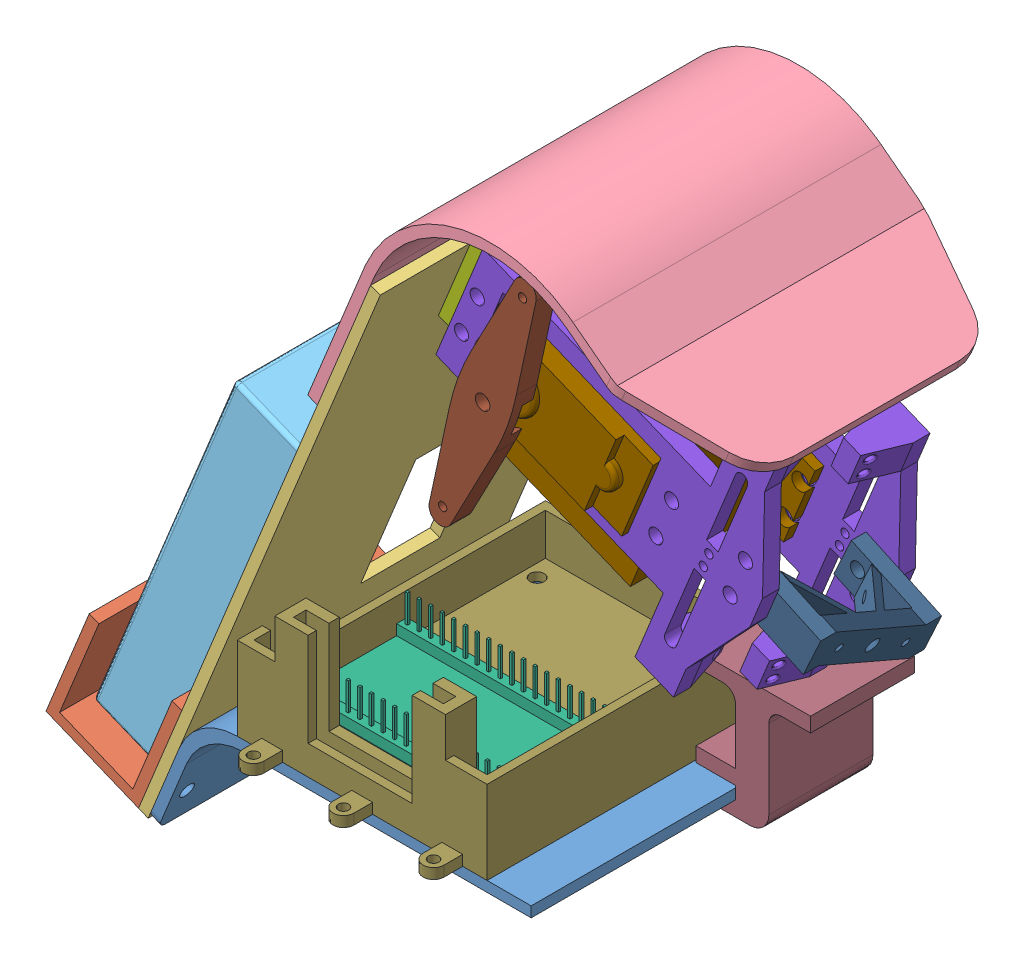
SolidWorks assembly Assieme_Completo, configuration Exploded View. Lengths in mm.
Overall size (179.46 180.65 88).
16 component instances, 13 part files, 47 mates.
Components (placement in the parent):
- Base_Shoulder Adapter-1: Base_Shoulder Adapter [Default] at (14.4604 -35.6109 54.9903)
- Cover_Battery and Switch-1: Cover_Battery and Switch [Default] at (-60.5554 -18.3009 91.9903) x (0.953748 0.300607 0) z (0 0 1)
- Cover_002 - Longer of 2.5-1: Cover_002 - Longer of 2.5 [Default] at (-58.2406 -19.2451 91.9903) x (0.953748 0.300607 0) z (0 0 1) size (96.21 115.11 74)
- Cover_Upper Closure-1: Cover_Upper Closure [Default] at (-46.3167 6.0165 91.9903) x (0.953748 0.300607 0) z (0 0 1)
- External_Battery-1: External_Battery [Default] at (-51.8934 26.7654 121.9903) x (-0.377678 -0.925937 0) z (0.925937 -0.377678 0)
- Internal_ESP-1: Internal_ESP [Default] at (-4.1009 8.2682 104.5288) x (0 0 1) z (1 0 0)
- ServoMotors_Adapter Back-1: ServoMotors_Adapter Back [Default] at (-2.1645 101.0239 81.755) x (0.377678 0.925937 0) z (0 0 1)
- ServoMotors_Main Adapter-1: ServoMotors_Main Adapter [Default] at (25.1522 96.5056 109.4903) x (0.377678 0.925937 0) z (0.925937 -0.377678 0)
- ServoMotor_Body-1: ServoMotor_Body [Default] at (13.3769 112.6484 76.9903) x (-0.377678 -0.925937 0) z (-0.925937 0.377678 0)
- ServoMotor_Body-2: ServoMotor_Body [Default] at (-2.1079 74.685 104.9903) x (0.377678 0.925937 0) z (-0.925937 0.377678 0)
- ServoMotors_Main Adapter-2: ServoMotors_Main Adapter [Default] at (17.5987 77.9868 72.4903) x (-0.377678 -0.925937 0) z (0.925937 -0.377678 0)
- ServoMotors_AdapterFront-1: ServoMotors_AdapterFront [Default] at (73.015 49.3207 76.2747) x (0.419505 0.907753 0) z (0 0 -1)
- ServoMotors_Adapter Wing-1: ServoMotors_Adapter Wing [Default] at (16.0553 97.422 62.5903) x (-0.284835 -0.958577 0) z (0 0 -1)
- ServoMotors_Adapter Wing-2: ServoMotors_Adapter Wing [Default] at (24.9883 116.5367 119.3903) x (-0.340492 -0.940247 0) z (0 0 1)
- Internal_Box_001-2: Internal_Box_001 [Default] at (-5.4581 5.274 91.9903) x (0 0 -1) z (1 0 0)
- Extra Support-1: Extra Support [Default] at (-26.7779 7.4821 54.9903) size (87 30 25)
Mates (geometry in assembly coordinates):
- Coincidente1: coincident aligned: plane of Cover_Battery and Switch-1 through (12.5109 85.2721 128.9903) normal (0 0 1); plane of Cover_002 - Longer of 2.5-1 through (24.2677 107.4764 128.9903) normal (0 0 1)
- Concentrico1: concentric aligned: cylinder of Cover_Battery and Switch-1 through (-50.1448 -16.6073 124.9903) axis (-0.925937 0.377678 0) radius 1.7; cylinder of Cover_002 - Longer of 2.5-1 through (-47.8299 -17.5515 124.9903) axis (-0.925937 0.377678 0) radius 1.7
- Coincidente2: coincident anti-aligned: plane of Cover_Battery and Switch-1 through (-58.2406 -19.2451 54.9903) normal (0.925937 -0.377678 0); plane of Cover_002 - Longer of 2.5-1 through (-58.2406 -19.2451 54.9903) normal (-0.925937 0.377678 0)
- Concentrico2: concentric aligned: cylinder of Cover_Battery and Switch-1 through (-50.1448 -16.6073 58.9903) axis (-0.925937 0.377678 0) radius 1.7; cylinder of Cover_002 - Longer of 2.5-1 through (-47.8299 -17.5515 58.9903) axis (-0.925937 0.377678 0) radius 1.7
- Coincidente3: coincident anti-aligned: plane of Cover_002 - Longer of 2.5-1 through (-58.2406 -19.2451 54.9903) normal (-0.925937 0.377678 0); plane of Cover_Upper Closure-1 through (-16.2316 83.7466 128.9903) normal (0.925937 -0.377678 0)
- Coincidente4: coincident aligned: plane of Cover_002 - Longer of 2.5-1 through (24.2677 107.4764 128.9903) normal (0 0 1); plane of Cover_Upper Closure-1 through (25.3375 105.6303 128.9903) normal (0 0 1)
- Concentrico3: concentric aligned: cylinder of Cover_002 - Longer of 2.5-1 through (-32.428 98.3175 82.3312) axis (0.925937 -0.377678 0) radius 1.7; cylinder of Cover_Upper Closure-1 through (-34.7429 99.2617 82.3312) axis (0.925937 -0.377678 0) radius 1.7
- Concentrico4: concentric aligned: cylinder of Cover_002 - Longer of 2.5-1 through (-24.3967 118.0076 98.5428) axis (0.925937 -0.377678 0) radius 1.7; cylinder of Cover_Upper Closure-1 through (-26.7115 118.9518 98.5428) axis (0.925937 -0.377678 0) radius 1.7
- Coincidente5: coincident anti-aligned: plane of Cover_Battery and Switch-1 through (-60.5554 -18.3009 54.9903) normal (-0.925937 0.377678 0); plane of External_Battery-1 through (-26.5644 65.0335 93.9903) normal (0.925937 -0.377678 0)
- Coincidente6: coincident anti-aligned: plane of Cover_Battery and Switch-1 through (-78.1482 -11.125 54.9903) normal (0.377678 0.925937 0); plane of External_Battery-1 through (-77.2223 -11.5027 93.9903) normal (-0.377678 -0.925937 0)
- Distanza1: distance = 7 mm aligned: plane of External_Battery-1 through (-51.8934 26.7654 121.9903) normal (0 0 1); plane of Cover_Battery and Switch-1 through (12.5109 85.2721 128.9903) normal (0 0 1)
- Coincidente8: coincident anti-aligned: plane of Base_Shoulder Adapter-1 through (-56.87 -22.5041 128.9903) normal (-0.925937 0.377678 0); plane of Cover_002 - Longer of 2.5-1 through (-55.9258 -20.1893 54.9903) normal (0.925937 -0.377678 0)
- Coincidente9: coincident aligned: plane of Base_Shoulder Adapter-1 through (14.4604 -35.6109 128.9903) normal (0 0 1); plane of Cover_002 - Longer of 2.5-1 through (24.2677 107.4764 128.9903) normal (0 0 1)
- Concentrico5: concentric aligned: cylinder of Base_Shoulder Adapter-1 through (25.3504 -47.4009 124.9903) axis (-0.925937 0.377678 0) radius 1.7; cylinder of Cover_002 - Longer of 2.5-1 through (-47.8299 -17.5515 124.9903) axis (-0.925937 0.377678 0) radius 1.7
- Concentrico6: concentric aligned: cylinder of Base_Shoulder Adapter-1 through (25.3504 -47.4009 58.9903) axis (-0.925937 0.377678 0) radius 1.7; cylinder of Cover_002 - Longer of 2.5-1 through (-47.8299 -17.5515 58.9903) axis (-0.925937 0.377678 0) radius 1.7
- Coincidente10: coincident anti-aligned: plane of Cover_002 - Longer of 2.5-1 through (-55.9258 -20.1893 54.9903) normal (0.925937 -0.377678 0); plane of ServoMotors_Adapter Back-1 through (-5.8682 102.5346 81.755) normal (-0.925937 0.377678 0)
- Concentrico10: concentric anti-aligned: cylinder of Cover_002 - Longer of 2.5-1 through (-24.3967 118.0076 98.5428) axis (0.925937 -0.377678 0) radius 1.7; cylinder of ServoMotors_Adapter Back-1 through (8.0111 104.7889 98.5428) axis (-0.925937 0.377678 0) radius 1.7
- Concentrico11: concentric anti-aligned: cylinder of Cover_002 - Longer of 2.5-1 through (-32.428 98.3175 82.3312) axis (0.925937 -0.377678 0) radius 1.7; cylinder of ServoMotors_Adapter Back-1 through (-0.0202 85.0987 82.3312) axis (-0.925937 0.377678 0) radius 1.7
- Coincidente14: coincident anti-aligned: plane of ServoMotors_Main Adapter-1 through (25.1522 96.5056 109.4903) normal (0 0 -1); plane of ServoMotor_Body-1 through (56.8959 94.8975 109.4903) normal (0 0 1)
- Coincidente15: coincident anti-aligned: plane of ServoMotors_Adapter Back-1 through (2.491 123.0286 107.2903) normal (0 0 1); plane of ServoMotor_Body-1 through (56.8959 94.8975 107.2903) normal (0 0 -1)
- Parallelo3: parallel aligned: line of ServoMotors_Adapter Back-1 through (2.491 123.0286 107.2903) axis (0.925937 -0.377678 0); line of ServoMotors_Main Adapter-1 through (8.0466 120.7625 113.4903) axis (0.925937 -0.377678 0)
- Concentrico12: concentric anti-aligned: cylinder of ServoMotors_Main Adapter-1 through (53.3409 90.9477 119.4903) axis (0 0 -1) radius 1.7; cylinder of ServoMotor_Body-1 through (53.3409 90.9477 102.4903) axis (0 0 1) radius 2
- Concentrico13: concentric anti-aligned: cylinder of ServoMotors_Main Adapter-1 through (49.5641 81.6883 119.4903) axis (0 0 -1) radius 1.7; cylinder of ServoMotor_Body-1 through (49.5641 81.6883 102.4903) axis (0 0 1) radius 2
- Coincidente17: coincident: line of ServoMotors_Adapter Back-1 through (2.491 123.0286 107.2903) axis (0.925937 -0.377678 0); plane of ServoMotors_Main Adapter-1 through (58.9732 99.9902 119.4903) normal (0.377678 0.925937 0)
- Coincidente20: coincident anti-aligned: plane of ServoMotor_Body-2 through (41.4111 56.9341 72.4903) normal (0 0 -1); plane of ServoMotors_Main Adapter-2 through (17.5987 77.9868 72.4903) normal (0 0 1)
- Concentrico14: concentric anti-aligned: cylinder of ServoMotor_Body-2 through (45.4096 71.503 79.4903) axis (0 0 -1) radius 2; cylinder of ServoMotors_Main Adapter-2 through (45.4096 71.503 62.4903) axis (0 0 1) radius 1.7
- Concentrico15: concentric anti-aligned: cylinder of ServoMotor_Body-2 through (-5.0344 81.2786 79.4903) axis (0 0 -1) radius 2; cylinder of ServoMotors_Main Adapter-2 through (-5.0344 81.2786 62.4903) axis (0 0 1) radius 1.7
- Coincidente21: coincident anti-aligned: plane of ServoMotors_Adapter Back-1 through (-16.5996 76.225 74.6903) normal (0 0 -1); plane of ServoMotor_Body-2 through (41.4111 56.9341 74.6903) normal (0 0 1)
- Parallelo5: parallel aligned: line of ServoMotors_Adapter Back-1 through (-5.2692 104.0031 74.6903) axis (0.925937 -0.377678 0); line of ServoMotors_Main Adapter-2 through (-0.2623 100.3919 72.4903) axis (0.925937 -0.377678 0)
- Distanza2: distance = 1 mm anti-aligned: plane of ServoMotor_Body-2 through (5.4457 93.2037 66.9903) normal (0.377678 0.925937 0); plane of ServoMotor_Body-1 through (5.8233 94.1297 114.9903) normal (-0.377678 -0.925937 0)
- Distanza4: distance = 2 mm anti-aligned: plane of ServoMotors_Main Adapter-1 through (-6.3051 85.5769 119.4903) normal (-0.925937 0.377678 0); plane of ServoMotors_Adapter Back-1 through (-2.1645 101.0239 81.755) normal (0.925937 -0.377678 0)
- Distanza5: distance = 2 mm anti-aligned: plane of ServoMotors_Main Adapter-2 through (2.7591 107.7994 62.4903) normal (-0.925937 0.377678 0); plane of ServoMotors_Adapter Back-1 through (-2.1645 101.0239 81.755) normal (0.925937 -0.377678 0)
- Concentrico16: concentric anti-aligned: cylinder of ServoMotors_Main Adapter-1 through (67.4164 78.326 108.4903) axis (0 0 1) radius 1.7; cylinder of ServoMotors_AdapterFront-1 through (67.4164 78.326 109.9603) axis (0 0 -1) radius 1.7
- Coincidente30: coincident anti-aligned: plane of ServoMotors_Main Adapter-1 through (25.1522 96.5056 109.4903) normal (0 0 -1); plane of ServoMotors_AdapterFront-1 through (67.0176 84.0184 109.4903) normal (0 0 1)
- Concentrico19: concentric anti-aligned: cylinder of ServoMotors_Main Adapter-1 through (67.4164 78.326 108.4903) axis (0 0 1) radius 1.7; cylinder of ServoMotors_AdapterFront-1 through (67.4164 78.326 109.9603) axis (0 0 -1) radius 1.7
- Parallelo10: parallel anti-aligned: plane of ServoMotors_Main Adapter-2 through (17.5987 77.9868 72.4903) normal (0 0 1); plane of ServoMotors_AdapterFront-1 through (59.055 66.7884 72.4947) normal (0 0 -1)
- Coincidente33: coincident anti-aligned: plane of ServoMotor_Body-2 through (10.9283 80.1676 59.9903) normal (0 0 -1); plane of ServoMotors_Adapter Wing-1 through (1.2309 74.9131 59.9903) normal (0 0 1)
- Concentrico23: concentric anti-aligned: cylinder of ServoMotor_Body-2 through (10.9283 80.1676 64.9903) axis (0 0 -1) radius 1.25; cylinder of ServoMotors_Adapter Wing-1 through (10.9283 80.1676 57.5903) axis (0 0 1) radius 1.75
- Coincidente34: coincident anti-aligned: plane of ServoMotor_Body-1 through (18.8595 99.6123 121.9903) normal (0 0 1); plane of ServoMotors_Adapter Wing-2 through (23.537 89.6238 121.9903) normal (0 0 -1)
- Concentrico24: concentric anti-aligned: cylinder of ServoMotor_Body-1 through (18.8595 99.6123 116.9903) axis (0 0 1) radius 1.25; cylinder of ServoMotors_Adapter Wing-2 through (18.8595 99.6123 124.3903) axis (0 0 -1) radius 1.75
- Coincidente36: coincident anti-aligned: plane of Base_Shoulder Adapter-1 through (-45.5396 5.274 128.9903) normal (0 1 0); plane of Internal_Box_001-2 through (-5.4581 5.274 91.9903) normal (0 -1 0)
- Concentrico28: concentric anti-aligned: cylinder of Base_Shoulder Adapter-1 through (-30.4581 -4.726 61.9903) axis (0 1 0) radius 1.7; cylinder of Internal_Box_001-2 through (-30.4581 13.274 61.9903) axis (0 -1 0) radius 1.7
- Concentrico29: concentric anti-aligned: cylinder of Base_Shoulder Adapter-1 through (19.5419 -4.726 121.9903) axis (0 1 0) radius 1.7; cylinder of Internal_Box_001-2 through (19.5419 13.274 121.9903) axis (0 -1 0) radius 1.7
- Distanza6: distance = 3 mm anti-aligned: plane of Internal_ESP-1 through (19.8827 11.9521 118.4903) normal (0 0 1); plane of Internal_Box_001-2 through (-5.4581 34.774 121.4903) normal (0 0 -1)
- Coincidente37: coincident aligned: line of Base_Shoulder Adapter-1 through (-33.7779 2.774 128.9903) axis (0 0 -1); line of Extra Support-1 through (-33.7779 2.774 79.9903) axis (0 0 -1)
- Coincidente38: coincident anti-aligned: plane of Base_Shoulder Adapter-1 through (-43.8594 2.774 128.9903) normal (0 -1 0); plane of Extra Support-1 through (43.2221 2.774 79.9903) normal (0 1 0)
- Coincidente39: coincident aligned: plane of Base_Shoulder Adapter-1 through (14.4604 -35.6109 54.9903) normal (0 0 -1); plane of Extra Support-1 through (-26.7779 7.4821 54.9903) normal (0 0 -1)
